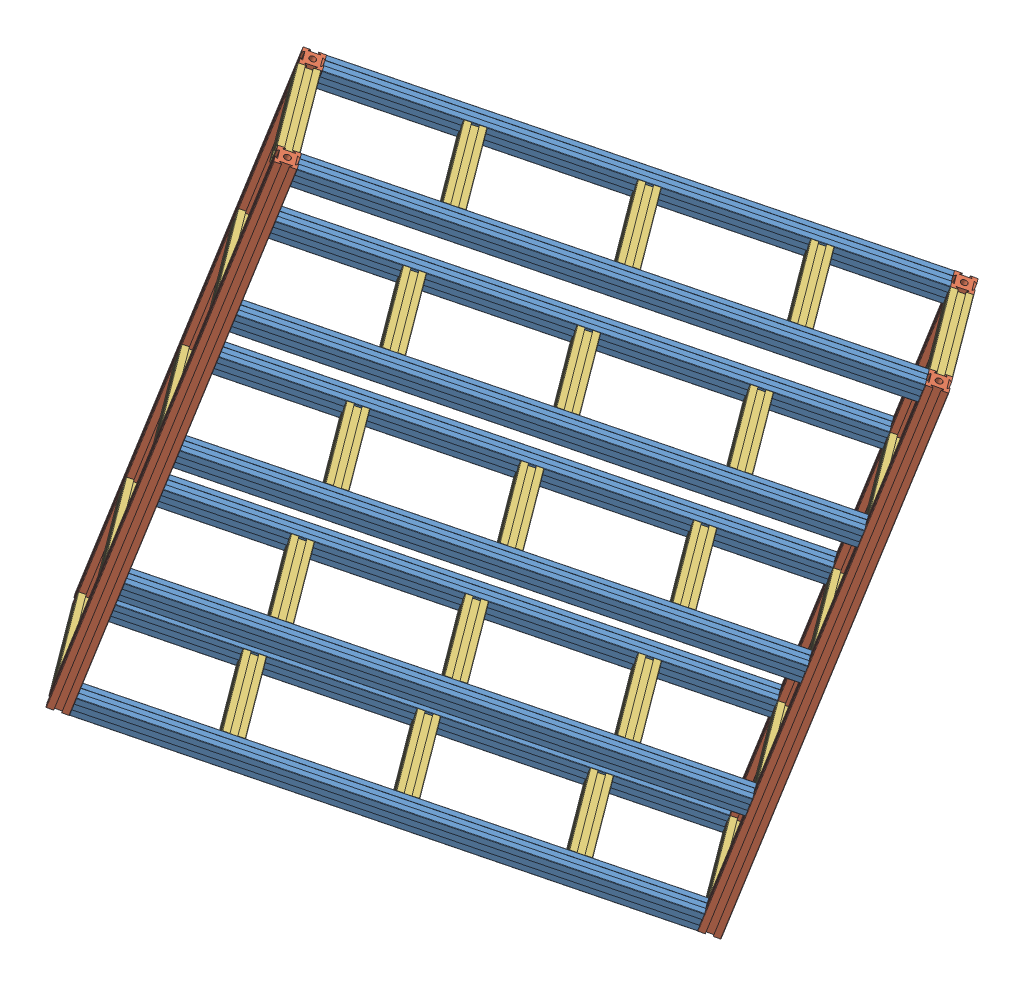
SolidWorks assembly Rack, configuration Default. Lengths in mm.
Overall size (710.4 790.88 509.16).
39 component instances, 3 part files, 86 mates.
Components (placement in the parent):
- Aluminium_Extrusion_4-1: Aluminium_Extrusion_4 [Default] at (-556.3348 883.7436 734.2395) x (-0.306101 -0.946689 0.100409) z (0.57653 -0.100409 0.810883) size (20 533.4 20)
- Aluminium_Extrusion_25-1: Aluminium_Extrusion_25 [Default] at (-346.6204 119.3218 490.4781) x (0.757572 -0.306101 -0.57653) z (0.57653 -0.100409 0.810883) size (20 635 20)
- Aluminium_Extrusion_25-2: Aluminium_Extrusion_25 [Default] at (-765.8605 288.7181 809.5301) x (0.757572 -0.306101 -0.57653) z (0.57653 -0.100409 0.810883) size (20 635 20)
- Aluminium_Extrusion_4-2: Aluminium_Extrusion_4 [Default] at (-703.6871 428.0226 782.575) x (-0.306101 -0.946689 0.100409) z (0.57653 -0.100409 0.810883) size (20 533.4 20)
- Aluminium_Extrusion_4-3: Aluminium_Extrusion_4 [Default] at (-744.587 301.5299 795.9913) x (-0.306101 -0.946689 0.100409) z (0.57653 -0.100409 0.810883) size (20 533.4 20)
- Aluminium_Extrusion_4-4: Aluminium_Extrusion_4 [Default] at (-656.4045 574.255 767.0651) x (-0.306101 -0.946689 0.100409) z (0.57653 -0.100409 0.810883) size (20 533.4 20)
- Aluminium_Extrusion_4-5: Aluminium_Extrusion_4 [Default] at (-608.1287 723.559 751.2293) x (-0.306101 -0.946689 0.100409) z (0.57653 -0.100409 0.810883) size (20 533.4 20)
- Aluminium_Extrusion_4-11: Aluminium_Extrusion_4 [Default] at (-633.581 415.8128 881.1783) x (-0.306101 -0.946689 0.100409) z (0.57653 -0.100409 0.810883) size (20 533.4 20)
- Aluminium_Extrusion_4-12: Aluminium_Extrusion_4 [Default] at (-538.0226 711.3492 849.8327) x (-0.306101 -0.946689 0.100409) z (0.57653 -0.100409 0.810883) size (20 533.4 20)
- Aluminium_Extrusion_4-13: Aluminium_Extrusion_4 [Default] at (-674.4809 289.3201 894.5946) x (-0.306101 -0.946689 0.100409) z (0.57653 -0.100409 0.810883) size (20 533.4 20)
- Aluminium_Extrusion_4-14: Aluminium_Extrusion_4 [Default] at (-586.2984 562.0452 865.6684) x (-0.306101 -0.946689 0.100409) z (0.57653 -0.100409 0.810883) size (20 533.4 20)
- Aluminium_Extrusion_25-7: Aluminium_Extrusion_25 [Default] at (-276.5142 107.112 589.0815) x (0.757572 -0.306101 -0.57653) z (0.57653 -0.100409 0.810883) size (20 635 20)
- Aluminium_Extrusion_4-15: Aluminium_Extrusion_4 [Default] at (-486.2287 871.5338 832.8429) x (-0.306101 -0.946689 0.100409) z (0.57653 -0.100409 0.810883) size (20 533.4 20)
- Aluminium_Extrusion_25-8: Aluminium_Extrusion_25 [Default] at (-695.7544 276.5083 908.1334) x (0.757572 -0.306101 -0.57653) z (0.57653 -0.100409 0.810883) size (20 635 20)
- Aluminium_Extrusion_21-16: Aluminium_Extrusion_21 [Default] at (-99.7927 691.3339 511.1121) x (0.306101 0.946689 -0.100409) z (-0.757572 0.306101 0.57653) size (20 101.6 20)
- Aluminium_Extrusion_21-17: Aluminium_Extrusion_21 [Default] at (-189.5655 727.6071 579.4314) x (0.306101 0.946689 -0.100409) z (-0.757572 0.306101 0.57653) size (20 101.6 20)
- Aluminium_Extrusion_21-18: Aluminium_Extrusion_21 [Default] at (-300.8229 772.5613 664.101) x (0.306101 0.946689 -0.100409) z (-0.757572 0.306101 0.57653) size (20 101.6 20)
- Aluminium_Extrusion_21-19: Aluminium_Extrusion_21 [Default] at (-412.8854 817.8408 749.3832) x (0.306101 0.946689 -0.100409) z (-0.757572 0.306101 0.57653) size (20 101.6 20)
- Aluminium_Extrusion_21-20: Aluminium_Extrusion_21 [Default] at (-519.7495 861.0199 830.7094) x (0.306101 0.946689 -0.100409) z (-0.757572 0.306101 0.57653) size (20 101.6 20)
- Aluminium_Extrusion_21-21: Aluminium_Extrusion_21 [Default] at (-570.8267 700.5456 847.1538) x (0.306101 0.946689 -0.100409) z (-0.757572 0.306101 0.57653) size (20 101.6 20)
- Aluminium_Extrusion_21-22: Aluminium_Extrusion_21 [Default] at (-464.6793 657.6561 766.373) x (0.306101 0.946689 -0.100409) z (-0.757572 0.306101 0.57653) size (20 101.6 20)
- Aluminium_Extrusion_21-23: Aluminium_Extrusion_21 [Default] at (-352.6168 612.3767 681.0907) x (0.306101 0.946689 -0.100409) z (-0.757572 0.306101 0.57653) size (20 101.6 20)
- Aluminium_Extrusion_21-24: Aluminium_Extrusion_21 [Default] at (-241.3594 567.4225 596.4212) x (0.306101 0.946689 -0.100409) z (-0.757572 0.306101 0.57653) size (20 101.6 20)
- Aluminium_Extrusion_21-25: Aluminium_Extrusion_21 [Default] at (-151.5866 531.1493 528.1019) x (0.306101 0.946689 -0.100409) z (-0.757572 0.306101 0.57653) size (20 101.6 20)
- Aluminium_Extrusion_21-27: Aluminium_Extrusion_21 [Default] at (-178.5755 394.6985 530.3944) x (-0.306101 -0.946689 0.100409) z (0.757572 -0.306101 -0.57653) size (20 101.6 20)
- Aluminium_Extrusion_21-28: Aluminium_Extrusion_21 [Default] at (-268.3483 430.9717 598.7137) x (-0.306101 -0.946689 0.100409) z (0.757572 -0.306101 -0.57653) size (20 101.6 20)
- Aluminium_Extrusion_21-29: Aluminium_Extrusion_21 [Default] at (-379.6057 475.9259 683.3833) x (-0.306101 -0.946689 0.100409) z (0.757572 -0.306101 -0.57653) size (20 101.6 20)
- Aluminium_Extrusion_21-30: Aluminium_Extrusion_21 [Default] at (-491.6682 521.2053 768.6656) x (-0.306101 -0.946689 0.100409) z (0.757572 -0.306101 -0.57653) size (20 101.6 20)
- Aluminium_Extrusion_21-31: Aluminium_Extrusion_21 [Default] at (-597.8156 564.0948 849.4463) x (-0.306101 -0.946689 0.100409) z (0.757572 -0.306101 -0.57653) size (20 101.6 20)
- Aluminium_Extrusion_21-57: Aluminium_Extrusion_21 [Default] at (-666.3674 405.0637 878.4937) x (0.306101 0.946689 -0.100409) z (-0.757572 0.306101 0.57653) size (20 101.6 20)
- Aluminium_Extrusion_21-58: Aluminium_Extrusion_21 [Default] at (-560.22 362.1742 797.7129) x (0.306101 0.946689 -0.100409) z (-0.757572 0.306101 0.57653) size (20 101.6 20)
- Aluminium_Extrusion_21-59: Aluminium_Extrusion_21 [Default] at (-448.1575 316.8947 712.4307) x (0.306101 0.946689 -0.100409) z (-0.757572 0.306101 0.57653) size (20 101.6 20)
- Aluminium_Extrusion_21-60: Aluminium_Extrusion_21 [Default] at (-336.9001 271.9405 627.7611) x (0.306101 0.946689 -0.100409) z (-0.757572 0.306101 0.57653) size (20 101.6 20)
- Aluminium_Extrusion_21-61: Aluminium_Extrusion_21 [Default] at (-247.1273 235.6673 559.4418) x (0.306101 0.946689 -0.100409) z (-0.757572 0.306101 0.57653) size (20 101.6 20)
- Aluminium_Extrusion_21-67: Aluminium_Extrusion_21 [Default] at (-686.0053 291.3476 878.3749) x (-0.306101 -0.946689 0.100409) z (0.757572 -0.306101 -0.57653) size (20 101.6 20)
- Aluminium_Extrusion_21-68: Aluminium_Extrusion_21 [Default] at (-579.8578 248.4582 797.5941) x (-0.306101 -0.946689 0.100409) z (0.757572 -0.306101 -0.57653) size (20 101.6 20)
- Aluminium_Extrusion_21-69: Aluminium_Extrusion_21 [Default] at (-467.7954 203.1787 712.3119) x (-0.306101 -0.946689 0.100409) z (0.757572 -0.306101 -0.57653) size (20 101.6 20)
- Aluminium_Extrusion_21-70: Aluminium_Extrusion_21 [Default] at (-356.538 158.2245 627.6423) x (-0.306101 -0.946689 0.100409) z (0.757572 -0.306101 -0.57653) size (20 101.6 20)
- Aluminium_Extrusion_21-71: Aluminium_Extrusion_21 [Default] at (-266.7651 121.9513 559.323) x (-0.306101 -0.946689 0.100409) z (0.757572 -0.306101 -0.57653) size (20 101.6 20)
Mates (geometry in assembly coordinates):
- Coincident10: coincident anti-aligned: plane of Aluminium_Extrusion_4-1 through (-556.3348 883.7436 734.2395) normal (-0.757572 0.306101 0.57653); plane of Aluminium_Extrusion_25-2 through (-556.3348 883.7436 734.2395) normal (0.757572 -0.306101 -0.57653)
- Coincident11: coincident aligned: plane of Aluminium_Extrusion_4-1 through (-152.2461 720.4693 426.7182) normal (0.57653 -0.100409 0.810883); plane of Aluminium_Extrusion_25-2 through (-571.4863 889.8656 745.7702) normal (0.57653 -0.100409 0.810883)
- Coincident12: coincident aligned: plane of Aluminium_Extrusion_4-1 through (-152.2461 720.4693 426.7182) normal (0.306101 0.946689 -0.100409); plane of Aluminium_Extrusion_25-2 through (-571.4863 889.8656 745.7702) normal (0.306101 0.946689 -0.100409)
- Coincident13: coincident anti-aligned: plane of Aluminium_Extrusion_4-1 through (-152.2461 720.4693 426.7182) normal (0.757572 -0.306101 -0.57653); plane of Aluminium_Extrusion_25-1 through (-152.2461 720.4693 426.7182) normal (-0.757572 0.306101 0.57653)
- Coincident14: coincident aligned: plane of Aluminium_Extrusion_4-1 through (-152.2461 720.4693 426.7182) normal (0.57653 -0.100409 0.810883); plane of Aluminium_Extrusion_25-1 through (-152.2461 720.4693 426.7182) normal (0.57653 -0.100409 0.810883)
- Coincident15: coincident aligned: plane of Aluminium_Extrusion_4-1 through (-152.2461 720.4693 426.7182) normal (0.306101 0.946689 -0.100409); plane of Aluminium_Extrusion_25-1 through (-152.2461 720.4693 426.7182) normal (0.306101 0.946689 -0.100409)
- Coincident16: coincident anti-aligned: plane of Aluminium_Extrusion_25-1 through (-152.2461 720.4693 426.7182) normal (-0.757572 0.306101 0.57653); plane of Aluminium_Extrusion_4-3 through (-340.4983 138.2555 488.47) normal (0.757572 -0.306101 -0.57653)
- Coincident17: coincident aligned: plane of Aluminium_Extrusion_25-1 through (-152.2461 720.4693 426.7182) normal (0.57653 -0.100409 0.810883); plane of Aluminium_Extrusion_4-3 through (-340.4983 138.2555 488.47) normal (0.57653 -0.100409 0.810883)
- Coincident18: coincident aligned: plane of Aluminium_Extrusion_25-1 through (-346.6204 119.3218 490.4781) normal (-0.306101 -0.946689 0.100409); plane of Aluminium_Extrusion_4-3 through (-346.6204 119.3218 490.4781) normal (-0.306101 -0.946689 0.100409)
- Coincident19: coincident aligned: plane of Aluminium_Extrusion_25-2 through (-571.4863 889.8656 745.7702) normal (0.57653 -0.100409 0.810883); plane of Aluminium_Extrusion_4-3 through (-340.4983 138.2555 488.47) normal (0.57653 -0.100409 0.810883)
- Coincident20: coincident aligned: plane of Aluminium_Extrusion_25-2 through (-765.8605 288.7181 809.5301) normal (-0.306101 -0.946689 0.100409); plane of Aluminium_Extrusion_4-3 through (-346.6204 119.3218 490.4781) normal (-0.306101 -0.946689 0.100409)
- Coincident21: coincident anti-aligned: plane of Aluminium_Extrusion_25-1 through (-152.2461 720.4693 426.7182) normal (-0.757572 0.306101 0.57653); plane of Aluminium_Extrusion_4-2 through (-299.5983 264.7483 475.0537) normal (0.757572 -0.306101 -0.57653)
- Coincident22: coincident aligned: plane of Aluminium_Extrusion_25-1 through (-152.2461 720.4693 426.7182) normal (0.57653 -0.100409 0.810883); plane of Aluminium_Extrusion_4-2 through (-299.5983 264.7483 475.0537) normal (0.57653 -0.100409 0.810883)
- Coincident23: coincident anti-aligned: plane of Aluminium_Extrusion_25-1 through (-152.2461 720.4693 426.7182) normal (-0.757572 0.306101 0.57653); plane of Aluminium_Extrusion_4-5 through (-204.04 560.2846 443.708) normal (0.757572 -0.306101 -0.57653)
- Coincident24: coincident aligned: plane of Aluminium_Extrusion_25-1 through (-152.2461 720.4693 426.7182) normal (0.57653 -0.100409 0.810883); plane of Aluminium_Extrusion_4-5 through (-204.04 560.2846 443.708) normal (0.57653 -0.100409 0.810883)
- Coincident25: coincident anti-aligned: plane of Aluminium_Extrusion_25-1 through (-152.2461 720.4693 426.7182) normal (-0.757572 0.306101 0.57653); plane of Aluminium_Extrusion_4-4 through (-252.3158 410.9807 459.5437) normal (0.757572 -0.306101 -0.57653)
- Coincident26: coincident aligned: plane of Aluminium_Extrusion_25-1 through (-152.2461 720.4693 426.7182) normal (0.57653 -0.100409 0.810883); plane of Aluminium_Extrusion_4-4 through (-252.3158 410.9807 459.5437) normal (0.57653 -0.100409 0.810883)
- Coincident27: coincident aligned: plane of Aluminium_Extrusion_25-5 through (-130.7535 198.712 1001.5793) normal (0.306101 0.946689 -0.100409); plane of Aluminium_Extrusion_21-10 through (-130.7535 198.712 1001.5793) normal (0.306101 0.946689 -0.100409)
- Coincident28: coincident anti-aligned: plane of Aluminium_Extrusion_25-5 through (-130.7535 198.712 1001.5793) normal (-0.757572 0.306101 0.57653); plane of Aluminium_Extrusion_21-10 through (-130.7535 198.712 1001.5793) normal (0.757572 -0.306101 -0.57653)
- Coincident29: coincident anti-aligned: plane of Aluminium_Extrusion_21-10 through (-534.8422 361.9863 1309.1007) normal (-0.757572 0.306101 0.57653); plane of Aluminium_Extrusion_25-6 through (-534.8422 361.9863 1309.1007) normal (0.757572 -0.306101 -0.57653)
- Coincident30: coincident aligned: plane of Aluminium_Extrusion_21-10 through (-130.7535 198.712 1001.5793) normal (0.57653 -0.100409 0.810883); plane of Aluminium_Extrusion_25-6 through (-549.9936 368.1084 1320.6313) normal (0.57653 -0.100409 0.810883)
- Coincident31: coincident aligned: plane of Aluminium_Extrusion_21-10 through (-130.7535 198.712 1001.5793) normal (0.306101 0.946689 -0.100409); plane of Aluminium_Extrusion_25-6 through (-549.9936 368.1084 1320.6313) normal (0.306101 0.946689 -0.100409)
- Coincident32: coincident aligned: plane of Aluminium_Extrusion_25-5 through (-130.7535 198.712 1001.5793) normal (0.57653 -0.100409 0.810883); plane of Aluminium_Extrusion_21-10 through (-130.7535 198.712 1001.5793) normal (0.57653 -0.100409 0.810883)
- Coincident33: coincident aligned: plane of Aluminium_Extrusion_21-8 through (-325.1277 -402.4355 1065.3393) normal (-0.306101 -0.946689 0.100409); plane of Aluminium_Extrusion_25-5 through (-325.1277 -402.4355 1065.3393) normal (-0.306101 -0.946689 0.100409)
- Coincident34: coincident aligned: plane of Aluminium_Extrusion_21-8 through (-325.1277 -402.4355 1065.3393) normal (-0.306101 -0.946689 0.100409); plane of Aluminium_Extrusion_25-6 through (-744.3678 -233.0392 1384.3912) normal (-0.306101 -0.946689 0.100409)
- Coincident37: coincident aligned: plane of Aluminium_Extrusion_21-8 through (-319.0057 -383.5017 1063.3311) normal (0.57653 -0.100409 0.810883); plane of Aluminium_Extrusion_25-6 through (-549.9936 368.1084 1320.6313) normal (0.57653 -0.100409 0.810883)
- Coincident38: coincident aligned: plane of Aluminium_Extrusion_21-8 through (-319.0057 -383.5017 1063.3311) normal (0.57653 -0.100409 0.810883); plane of Aluminium_Extrusion_25-5 through (-130.7535 198.712 1001.5793) normal (0.57653 -0.100409 0.810883)
- Coincident39: coincident anti-aligned: plane of Aluminium_Extrusion_21-8 through (-319.0057 -383.5017 1063.3311) normal (0.757572 -0.306101 -0.57653); plane of Aluminium_Extrusion_25-5 through (-130.7535 198.712 1001.5793) normal (-0.757572 0.306101 0.57653)
- Coincident40: coincident anti-aligned: plane of Aluminium_Extrusion_21-9 through (-230.8231 -110.7766 1034.4049) normal (0.757572 -0.306101 -0.57653); plane of Aluminium_Extrusion_25-5 through (-130.7535 198.712 1001.5793) normal (-0.757572 0.306101 0.57653)
- Coincident41: coincident anti-aligned: plane of Aluminium_Extrusion_21-7 through (-182.5473 38.5274 1018.5691) normal (0.757572 -0.306101 -0.57653); plane of Aluminium_Extrusion_25-5 through (-130.7535 198.712 1001.5793) normal (-0.757572 0.306101 0.57653)
- Coincident42: coincident aligned: plane of Aluminium_Extrusion_21-7 through (-182.5473 38.5274 1018.5691) normal (0.57653 -0.100409 0.810883); plane of Aluminium_Extrusion_25-5 through (-130.7535 198.712 1001.5793) normal (0.57653 -0.100409 0.810883)
- Coincident43: coincident aligned: plane of Aluminium_Extrusion_21-9 through (-230.8231 -110.7766 1034.4049) normal (0.57653 -0.100409 0.810883); plane of Aluminium_Extrusion_25-5 through (-130.7535 198.712 1001.5793) normal (0.57653 -0.100409 0.810883)
- Distance1: distance = 149.2051 mm anti-aligned: plane of Aluminium_Extrusion_21-1 through (-158.3682 701.5355 428.7264) normal (-0.306101 -0.946689 0.100409); plane of Aluminium_Extrusion_21-5 through (-204.04 560.2846 443.708) normal (0.306101 0.946689 -0.100409)
- Distance2: distance = 137.7117 mm anti-aligned: plane of Aluminium_Extrusion_21-4 through (-252.3158 410.9807 459.5437) normal (0.306101 0.946689 -0.100409); plane of Aluminium_Extrusion_21-5 through (-210.162 541.3509 445.7162) normal (-0.306101 -0.946689 0.100409)
- Distance3: distance = 134.4672 mm anti-aligned: plane of Aluminium_Extrusion_21-2 through (-299.5983 264.7483 475.0537) normal (0.306101 0.946689 -0.100409); plane of Aluminium_Extrusion_21-4 through (-258.4378 392.0469 461.5519) normal (-0.306101 -0.946689 0.100409)
- Coincident47: coincident aligned: plane of Aluminium_Extrusion_25-7 through (-82.14 708.2595 525.3215) normal (0.306101 0.946689 -0.100409); plane of Aluminium_Extrusion_4-15 through (-82.14 708.2595 525.3215) normal (0.306101 0.946689 -0.100409)
- Coincident48: coincident anti-aligned: plane of Aluminium_Extrusion_25-7 through (-82.14 708.2595 525.3215) normal (-0.757572 0.306101 0.57653); plane of Aluminium_Extrusion_4-15 through (-82.14 708.2595 525.3215) normal (0.757572 -0.306101 -0.57653)
- Distance4: distance = 149.2051 mm anti-aligned: plane of Aluminium_Extrusion_21-15 through (-88.2621 689.3257 527.3297) normal (-0.306101 -0.946689 0.100409); plane of Aluminium_Extrusion_21-12 through (-133.9339 548.0749 542.3113) normal (0.306101 0.946689 -0.100409)
- Distance5: distance = 137.7117 mm anti-aligned: plane of Aluminium_Extrusion_21-14 through (-182.2097 398.7709 558.1471) normal (0.306101 0.946689 -0.100409); plane of Aluminium_Extrusion_21-12 through (-140.0559 529.1411 544.3195) normal (-0.306101 -0.946689 0.100409)
- Distance6: distance = 134.4672 mm anti-aligned: plane of Aluminium_Extrusion_21-11 through (-229.4922 252.5385 573.657) normal (0.306101 0.946689 -0.100409); plane of Aluminium_Extrusion_21-14 through (-188.3317 379.8371 560.1552) normal (-0.306101 -0.946689 0.100409)
- Coincident49: coincident anti-aligned: plane of Aluminium_Extrusion_4-15 through (-486.2287 871.5338 832.8429) normal (-0.757572 0.306101 0.57653); plane of Aluminium_Extrusion_25-8 through (-486.2287 871.5338 832.8429) normal (0.757572 -0.306101 -0.57653)
- Coincident50: coincident aligned: plane of Aluminium_Extrusion_4-15 through (-82.14 708.2595 525.3215) normal (0.57653 -0.100409 0.810883); plane of Aluminium_Extrusion_25-8 through (-501.3802 877.6559 844.3735) normal (0.57653 -0.100409 0.810883)
- Coincident51: coincident aligned: plane of Aluminium_Extrusion_4-15 through (-82.14 708.2595 525.3215) normal (0.306101 0.946689 -0.100409); plane of Aluminium_Extrusion_25-8 through (-501.3802 877.6559 844.3735) normal (0.306101 0.946689 -0.100409)
- Coincident52: coincident aligned: plane of Aluminium_Extrusion_25-7 through (-82.14 708.2595 525.3215) normal (0.57653 -0.100409 0.810883); plane of Aluminium_Extrusion_4-15 through (-82.14 708.2595 525.3215) normal (0.57653 -0.100409 0.810883)
- Coincident53: coincident aligned: plane of Aluminium_Extrusion_4-13 through (-276.5142 107.112 589.0815) normal (-0.306101 -0.946689 0.100409); plane of Aluminium_Extrusion_25-7 through (-276.5142 107.112 589.0815) normal (-0.306101 -0.946689 0.100409)
- Coincident54: coincident aligned: plane of Aluminium_Extrusion_4-13 through (-276.5142 107.112 589.0815) normal (-0.306101 -0.946689 0.100409); plane of Aluminium_Extrusion_25-8 through (-695.7544 276.5083 908.1334) normal (-0.306101 -0.946689 0.100409)
- Coincident55: coincident anti-aligned: plane of Aluminium_Extrusion_4-11 through (-229.4922 252.5385 573.657) normal (0.757572 -0.306101 -0.57653); plane of Aluminium_Extrusion_25-7 through (-82.14 708.2595 525.3215) normal (-0.757572 0.306101 0.57653)
- Coincident56: coincident aligned: plane of Aluminium_Extrusion_4-11 through (-229.4922 252.5385 573.657) normal (0.57653 -0.100409 0.810883); plane of Aluminium_Extrusion_25-7 through (-82.14 708.2595 525.3215) normal (0.57653 -0.100409 0.810883)
- Coincident57: coincident aligned: plane of Aluminium_Extrusion_4-13 through (-270.3922 126.0458 587.0733) normal (0.57653 -0.100409 0.810883); plane of Aluminium_Extrusion_25-8 through (-501.3802 877.6559 844.3735) normal (0.57653 -0.100409 0.810883)
- Coincident58: coincident aligned: plane of Aluminium_Extrusion_4-13 through (-270.3922 126.0458 587.0733) normal (0.57653 -0.100409 0.810883); plane of Aluminium_Extrusion_25-7 through (-82.14 708.2595 525.3215) normal (0.57653 -0.100409 0.810883)
- Coincident59: coincident anti-aligned: plane of Aluminium_Extrusion_4-13 through (-270.3922 126.0458 587.0733) normal (0.757572 -0.306101 -0.57653); plane of Aluminium_Extrusion_25-7 through (-82.14 708.2595 525.3215) normal (-0.757572 0.306101 0.57653)
- Coincident60: coincident anti-aligned: plane of Aluminium_Extrusion_4-14 through (-182.2097 398.7709 558.1471) normal (0.757572 -0.306101 -0.57653); plane of Aluminium_Extrusion_25-7 through (-82.14 708.2595 525.3215) normal (-0.757572 0.306101 0.57653)
- Coincident61: coincident anti-aligned: plane of Aluminium_Extrusion_4-12 through (-133.9339 548.0749 542.3113) normal (0.757572 -0.306101 -0.57653); plane of Aluminium_Extrusion_25-7 through (-82.14 708.2595 525.3215) normal (-0.757572 0.306101 0.57653)
- Coincident62: coincident aligned: plane of Aluminium_Extrusion_4-12 through (-133.9339 548.0749 542.3113) normal (0.57653 -0.100409 0.810883); plane of Aluminium_Extrusion_25-7 through (-82.14 708.2595 525.3215) normal (0.57653 -0.100409 0.810883)
- Coincident63: coincident aligned: plane of Aluminium_Extrusion_4-14 through (-182.2097 398.7709 558.1471) normal (0.57653 -0.100409 0.810883); plane of Aluminium_Extrusion_25-7 through (-82.14 708.2595 525.3215) normal (0.57653 -0.100409 0.810883)
- Coincident64: coincident aligned: plane of Aluminium_Extrusion_25-2 through (-571.4863 889.8656 745.7702) normal (-0.757572 0.306101 0.57653); plane of Aluminium_Extrusion_25-8 through (-501.3802 877.6559 844.3735) normal (-0.757572 0.306101 0.57653)
- Coincident65: coincident aligned: plane of Aluminium_Extrusion_4-1 through (-152.2461 720.4693 426.7182) normal (0.306101 0.946689 -0.100409); plane of Aluminium_Extrusion_4-15 through (-82.14 708.2595 525.3215) normal (0.306101 0.946689 -0.100409)
- Distance7: distance = 101.6 mm anti-aligned: plane of Aluminium_Extrusion_25-8 through (-512.9108 879.6641 828.1558) normal (-0.57653 0.100409 -0.810883); plane of Aluminium_Extrusion_25-2 through (-571.4863 889.8656 745.7702) normal (0.57653 -0.100409 0.810883)
- Coincident67: coincident anti-aligned: plane of Aluminium_Extrusion_25-7 through (-93.6706 710.2677 509.1039) normal (-0.57653 0.100409 -0.810883); plane of Aluminium_Extrusion_21-16 through (-99.7927 691.3339 511.1121) normal (0.57653 -0.100409 0.810883)
- Coincident69: coincident aligned: plane of Aluminium_Extrusion_25-7 through (-66.9886 702.1375 513.7909) normal (0.757572 -0.306101 -0.57653); plane of Aluminium_Extrusion_21-16 through (-143.2167 695.4135 417.1958) normal (0.757572 -0.306101 -0.57653)
- Coincident70: coincident aligned: plane of Aluminium_Extrusion_25-7 through (-82.14 708.2595 525.3215) normal (0.306101 0.946689 -0.100409); plane of Aluminium_Extrusion_21-16 through (-152.2461 720.4693 426.7182) normal (0.306101 0.946689 -0.100409)
- Coincident71: coincident aligned: plane of Aluminium_Extrusion_25-1 through (-152.2461 720.4693 426.7182) normal (0.306101 0.946689 -0.100409); plane of Aluminium_Extrusion_21-16 through (-152.2461 720.4693 426.7182) normal (0.306101 0.946689 -0.100409)
- Coincident72: coincident aligned: plane of Aluminium_Extrusion_25-1 through (-137.0947 714.3473 415.1876) normal (0.757572 -0.306101 -0.57653); plane of Aluminium_Extrusion_21-16 through (-143.2167 695.4135 417.1958) normal (0.757572 -0.306101 -0.57653)
- Coincident73: coincident anti-aligned: plane of Aluminium_Extrusion_4-15 through (-93.6706 710.2677 509.1039) normal (-0.57653 0.100409 -0.810883); plane of Aluminium_Extrusion_21-17 through (-189.5655 727.6071 579.4314) normal (0.57653 -0.100409 0.810883)
- Coincident74: coincident aligned: plane of Aluminium_Extrusion_4-15 through (-82.14 708.2595 525.3215) normal (0.306101 0.946689 -0.100409); plane of Aluminium_Extrusion_21-17 through (-242.019 756.7425 495.0375) normal (0.306101 0.946689 -0.100409)
- Coincident75: coincident anti-aligned: plane of Aluminium_Extrusion_4-15 through (-93.6706 710.2677 509.1039) normal (-0.57653 0.100409 -0.810883); plane of Aluminium_Extrusion_21-18 through (-300.8229 772.5613 664.101) normal (0.57653 -0.100409 0.810883)
- Coincident76: coincident aligned: plane of Aluminium_Extrusion_4-15 through (-82.14 708.2595 525.3215) normal (0.306101 0.946689 -0.100409); plane of Aluminium_Extrusion_21-18 through (-353.2764 801.6967 579.7071) normal (0.306101 0.946689 -0.100409)
- Coincident77: coincident anti-aligned: plane of Aluminium_Extrusion_4-15 through (-93.6706 710.2677 509.1039) normal (-0.57653 0.100409 -0.810883); plane of Aluminium_Extrusion_21-19 through (-412.8854 817.8408 749.3832) normal (0.57653 -0.100409 0.810883)
- Coincident78: coincident aligned: plane of Aluminium_Extrusion_4-15 through (-82.14 708.2595 525.3215) normal (0.306101 0.946689 -0.100409); plane of Aluminium_Extrusion_21-19 through (-465.3388 846.9762 664.9894) normal (0.306101 0.946689 -0.100409)
- Coincident79: coincident anti-aligned: plane of Aluminium_Extrusion_25-8 through (-512.9108 879.6641 828.1558) normal (-0.57653 0.100409 -0.810883); plane of Aluminium_Extrusion_21-20 through (-519.7495 861.0199 830.7094) normal (0.57653 -0.100409 0.810883)
- Coincident80: coincident aligned: plane of Aluminium_Extrusion_25-8 through (-501.3802 877.6559 844.3735) normal (0.306101 0.946689 -0.100409); plane of Aluminium_Extrusion_21-20 through (-572.203 890.1552 746.3156) normal (0.306101 0.946689 -0.100409)
- Coincident81: coincident anti-aligned: plane of Aluminium_Extrusion_25-1 through (-152.2461 720.4693 426.7182) normal (0.57653 -0.100409 0.810883); plane of Aluminium_Extrusion_21-25 through (-210.162 541.3509 445.7162) normal (-0.57653 0.100409 -0.810883)
- Coincident82: coincident aligned: plane of Aluminium_Extrusion_25-1 through (-137.0947 714.3473 415.1876) normal (0.757572 -0.306101 -0.57653); plane of Aluminium_Extrusion_21-25 through (-195.0106 535.2288 434.1856) normal (0.757572 -0.306101 -0.57653)
- Coincident83: coincident aligned: plane of Aluminium_Extrusion_4-5 through (-210.162 541.3509 445.7162) normal (-0.306101 -0.946689 0.100409); plane of Aluminium_Extrusion_21-25 through (-210.162 541.3509 445.7162) normal (-0.306101 -0.946689 0.100409)
- Coincident84: coincident anti-aligned: plane of Aluminium_Extrusion_4-12 through (-145.4645 550.083 526.0937) normal (-0.57653 0.100409 -0.810883); plane of Aluminium_Extrusion_21-24 through (-241.3594 567.4225 596.4212) normal (0.57653 -0.100409 0.810883)
- Coincident85: coincident aligned: plane of Aluminium_Extrusion_4-12 through (-133.9339 548.0749 542.3113) normal (0.306101 0.946689 -0.100409); plane of Aluminium_Extrusion_21-24 through (-293.8129 596.5579 512.0273) normal (0.306101 0.946689 -0.100409)
- Coincident86: coincident anti-aligned: plane of Aluminium_Extrusion_4-12 through (-145.4645 550.083 526.0937) normal (-0.57653 0.100409 -0.810883); plane of Aluminium_Extrusion_21-23 through (-352.6168 612.3767 681.0907) normal (0.57653 -0.100409 0.810883)
- Coincident88: coincident aligned: plane of Aluminium_Extrusion_4-12 through (-133.9339 548.0749 542.3113) normal (0.306101 0.946689 -0.100409); plane of Aluminium_Extrusion_21-23 through (-405.0702 641.512 596.6969) normal (0.306101 0.946689 -0.100409)
- Coincident89: coincident anti-aligned: plane of Aluminium_Extrusion_4-12 through (-145.4645 550.083 526.0937) normal (-0.57653 0.100409 -0.810883); plane of Aluminium_Extrusion_21-22 through (-464.6793 657.6561 766.373) normal (0.57653 -0.100409 0.810883)
- Coincident90: coincident aligned: plane of Aluminium_Extrusion_4-12 through (-133.9339 548.0749 542.3113) normal (0.306101 0.946689 -0.100409); plane of Aluminium_Extrusion_21-22 through (-517.1327 686.7915 681.9792) normal (0.306101 0.946689 -0.100409)
- Coincident91: coincident anti-aligned: plane of Aluminium_Extrusion_25-8 through (-512.9108 879.6641 828.1558) normal (-0.57653 0.100409 -0.810883); plane of Aluminium_Extrusion_21-21 through (-570.8267 700.5456 847.1538) normal (0.57653 -0.100409 0.810883)
- Coincident92: coincident aligned: plane of Aluminium_Extrusion_25-8 through (-501.3802 877.6559 844.3735) normal (-0.757572 0.306101 0.57653); plane of Aluminium_Extrusion_21-21 through (-629.4022 710.7472 764.7681) normal (-0.757572 0.306101 0.57653)
- Coincident93: coincident aligned: plane of Aluminium_Extrusion_4-12 through (-140.0559 529.1411 544.3195) normal (-0.306101 -0.946689 0.100409); plane of Aluminium_Extrusion_21-21 through (-629.4022 710.7472 764.7681) normal (-0.306101 -0.946689 0.100409)
- Coincident94: coincident aligned: plane of Aluminium_Extrusion_21-19 through (-471.4609 828.0424 666.9976) normal (-0.757572 0.306101 0.57653); plane of Aluminium_Extrusion_21-22 through (-523.2547 667.8577 683.9873) normal (-0.757572 0.306101 0.57653)
- Coincident95: coincident aligned: plane of Aluminium_Extrusion_21-18 through (-359.3984 782.7629 581.7153) normal (-0.757572 0.306101 0.57653); plane of Aluminium_Extrusion_21-23 through (-411.1923 622.5783 598.7051) normal (-0.757572 0.306101 0.57653)
- Coincident96: coincident aligned: plane of Aluminium_Extrusion_21-17 through (-248.141 737.8087 497.0457) normal (-0.757572 0.306101 0.57653); plane of Aluminium_Extrusion_21-24 through (-299.9349 577.6241 514.0355) normal (-0.757572 0.306101 0.57653)
